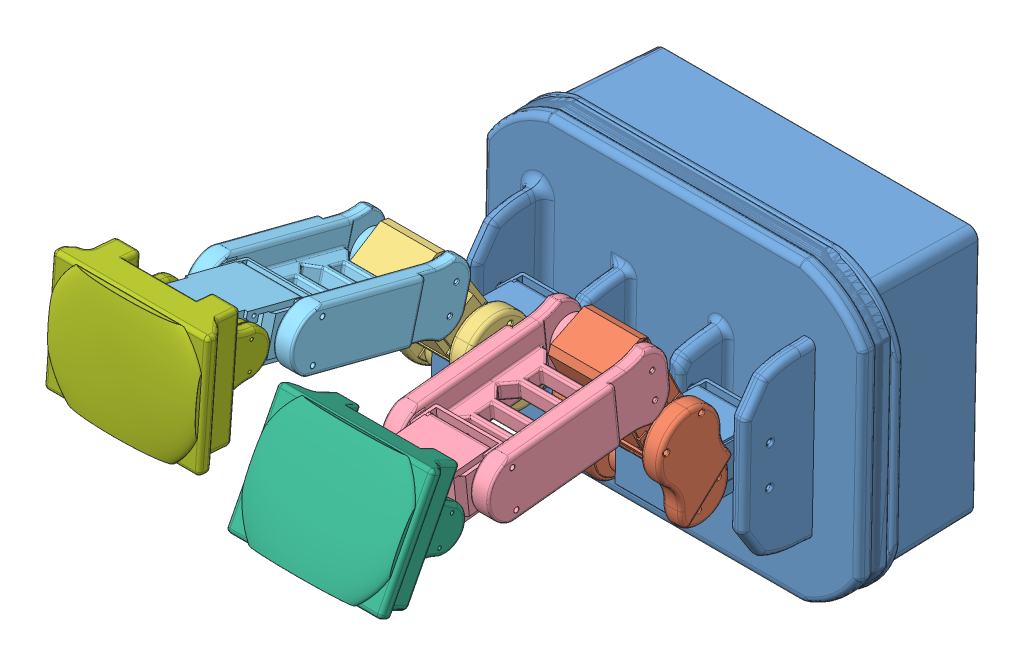
SolidWorks assembly Assem1, configuration Default. Lengths in mm.
Overall size (201.14 283.52 425.21).
7 component instances, 7 part files, 12 mates.
Components (placement in the parent):
- Base^Assem1-1: Base^Assem1 [Default] at (64.8941 222.3203 -121.5102) size (201.14 150.89 136.53)
- Thigh-1^Assem1-1: Thigh-1^Assem1 [Default] at (64.8941 -152.7287 50.029) x (1 0 0) z (0 0.978603 0.205757) size (57.23 42.16 92.78)
- Thigh-2^Assem1-1: Thigh-2^Assem1 [Default] at (64.8941 2.9525 -101.6103) x (1 0 0) z (0 0.633872 0.773438) size (57.23 47.23 92.08)
- Calf-1^Assem1-1: Calf-1^Assem1 [Default] at (64.8941 351.9232 -144.8266) x (1 0 0) z (0 -0.125131 0.99214) size (56.52 35.36 127.77)
- Calf-2^Assem1-1: Calf-2^Assem1 [Default] at (64.8941 409.7164 -94.2394) x (1 0 0) z (0 -0.401044 0.916059) size (56.52 94.64 110.97)
- Feet-1^Assem1-1: Feet-1^Assem1 [Default] at (64.8941 308.3801 -157.0394) x (1 0 0) z (0 -0.036475 0.999335) size (81.07 75.37 69.48)
- Feet-2^Assem1-1: Feet-2^Assem1 [Default] at (64.8941 415.4911 -91.0982) x (1 0 0) z (0 -0.417465 0.908693) size (81.06 75.42 69.39)
Mates (geometry in assembly coordinates):
- Concentric1: concentric anti-aligned: cylinder of Base^Assem1-1 through (141.7576 140.4743 195.312) axis (-1 0 0) radius 1.5; cylinder of Thigh-1^Assem1-1 through (92.7576 140.4743 195.312) axis (1 0 0) radius 4.25
- Coincident1: coincident anti-aligned: plane of Base^Assem1-1 through (125.2576 115.8229 209.6551) normal (1 0 0); plane of Thigh-1^Assem1-1 through (125.2576 140.4743 195.312) normal (-1 0 0)
- Concentric2: concentric aligned: cylinder of Base^Assem1-1 through (-14.7424 140.4743 195.312) axis (1 0 0) radius 1.5; cylinder of Thigh-2^Assem1-1 through (-1.7424 140.4743 195.312) axis (1 0 0) radius 4.25
- Coincident2: coincident anti-aligned: plane of Base^Assem1-1 through (1.7576 165.6737 208.6687) normal (-1 0 0); plane of Thigh-2^Assem1-1 through (1.7576 140.4743 195.312) normal (1 0 0)
- Concentric3: concentric anti-aligned: cylinder of Thigh-1^Assem1-1 through (141.7576 205.0145 225.6435) axis (-1 0 0) radius 1.5; cylinder of Calf-1^Assem1-1 through (125.2576 205.0145 225.6435) axis (1 0 0) radius 4.25
- Coincident4: coincident anti-aligned: plane of Thigh-1^Assem1-1 through (125.2576 206.5678 254.1216) normal (1 0 0); plane of Calf-1^Assem1-1 through (125.2576 205.0145 225.6435) normal (-1 0 0)
- Concentric4: concentric aligned: cylinder of Thigh-2^Assem1-1 through (-14.9174 200.3179 234.0958) axis (1 0 0) radius 1.5; cylinder of Calf-2^Assem1-1 through (30.5826 200.3179 234.0958) axis (1 0 0) radius 4.25
- Coincident5: coincident anti-aligned: plane of Thigh-2^Assem1-1 through (30.5826 235.9219 213.5559) normal (1 0 0); plane of Calf-2^Assem1-1 through (30.5826 200.3179 234.0958) normal (-1 0 0)
- Concentric5: concentric anti-aligned: cylinder of Calf-1^Assem1-1 through (79.8276 193.8278 332.6596) axis (1 0 0) radius 1.5; cylinder of Feet-1^Assem1-1 through (128.8276 193.8278 332.6596) axis (-1 0 0) radius 4.25
- Coincident7: coincident anti-aligned: plane of Calf-1^Assem1-1 through (125.3276 227.9823 355.5288) normal (1 0 0); plane of Feet-1^Assem1-1 through (125.3276 193.8278 332.6596) normal (-1 0 0)
- Concentric6: concentric aligned: cylinder of Calf-2^Assem1-1 through (-14.9174 227.201 338.2825) axis (1 0 0) radius 1.5; cylinder of Feet-2^Assem1-1 through (-1.9174 227.201 338.2825) axis (1 0 0) radius 4.25
- Coincident8: coincident anti-aligned: plane of Calf-2^Assem1-1 through (1.5826 254.8016 345.4671) normal (-1 0 0); plane of Feet-2^Assem1-1 through (1.5826 227.201 338.2825) normal (1 0 0)
